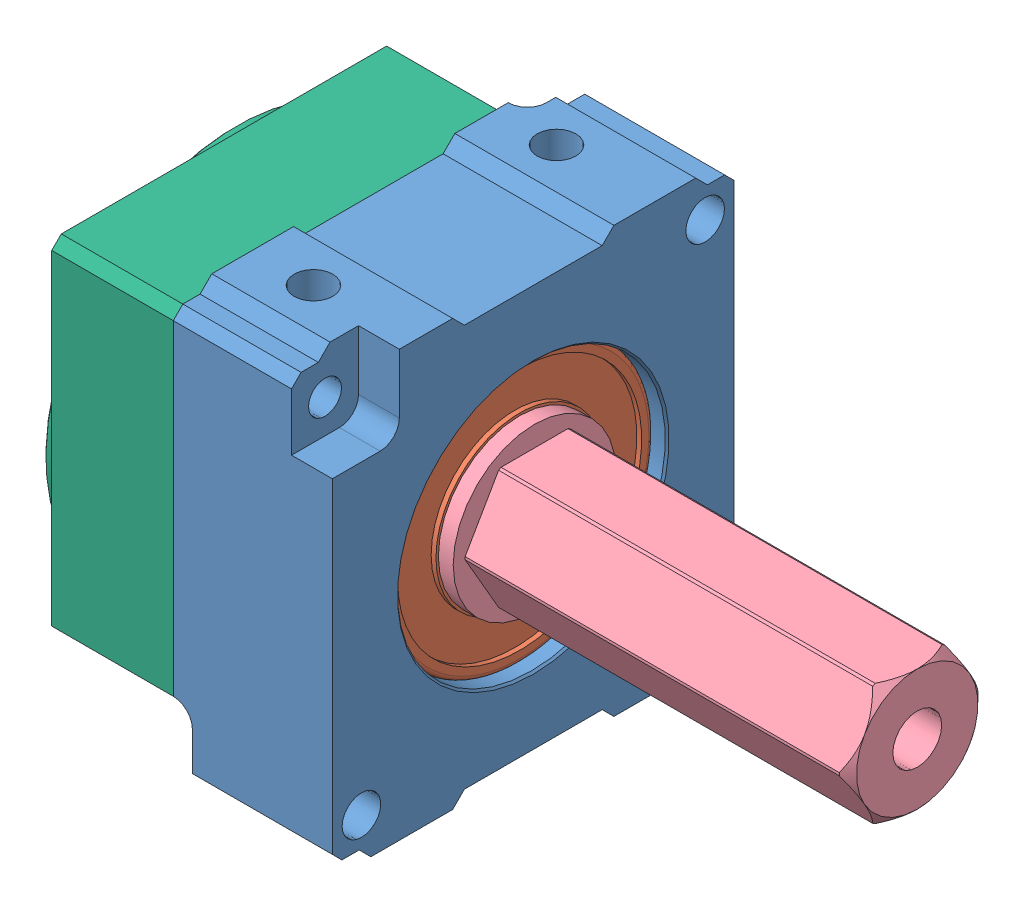
SolidWorks assembly v2-VersaPlanetary-1stage-with-775pro-20161031, configuration Default. Lengths in mm.
Overall size (71.25 44.45 42).
7 component instances, 6 part files, 13 mates.
Components (placement in the parent):
- 217-2625-026 Rev1-1: 217-2625-026 Rev1 [Default] at (-6.2575 -5.0341 -38.5492) x (0 -1 0) z (-1 0 0) size (44.45 42 18.13)
- 217-2742-001 Rev4-1: 217-2742-001 Rev4 [Default] at (-0.4115 -5.0341 -38.5492) x (1 0 0) z (0 0.976211 0.216822) size (7 28 28)
- 217-2742-001 Rev4-2: 217-2742-001 Rev4 [Default] at (8.4427 -5.0341 -38.5492) size (7 28 28)
- 217-2625-017 Rev1_9714K61-1: 217-2625-017 Rev1_9714K61 [Default] at (8.4427 -5.0341 -38.5492) x (0 0.932853 -0.360257) z (0 0.360257 0.932853) size (28.51 4.98 30.18)
- 217-2625-003 Rev1-1: 217-2625-003 Rev1 [Default] at (7.2409 -5.0341 -38.5492) x (0 -1 0) z (1 0 0) size (17 17 64.12)
- 217-2625-018 Rev1_98541A410-1: 217-2625-018 Rev1_98541A410 [Default] at (-0.9115 -4.635 -38.5422) x (1 0 0) z (0 -0.017452 0.999848) size (1 19.6 17.4)
- 217-2816-001 Rev1-1: 217-2816-001 Rev1 [Default] at (-6.1075 -5.0341 -38.5492) x (0 -1 0) z (1 0 0) size (42 42 14.5)
Mates (geometry in assembly coordinates):
- Concentric1: concentric aligned: cylinder of 217-2742-001 Rev4-1 through (-0.4115 -5.0341 -38.5492) axis (-1 0 0) radius 14; cylinder of 217-2742-001 Rev4-2 through (8.4427 -5.0341 -38.5492) axis (-1 0 0) radius 14
- Concentric2: concentric aligned: cylinder of 217-2742-001 Rev4-2 through (8.4427 -5.0341 -38.5492) axis (-1 0 0) radius 14; line of 217-2625-017 Rev1_9714K61-1 through (8.4427 -5.0341 -38.5492) axis (-1 0 0)
- Tangent3: tangent: plane of 217-2742-001 Rev4-2 through (8.4427 3.7159 -38.5492) normal (-1 0 0); face of 217-2625-017 Rev1_9714K61-1
- Tangent4: tangent: plane of 217-2742-001 Rev4-1 through (6.5885 -3.408 -45.8708) normal (1 0 0); face of 217-2625-017 Rev1_9714K61-1
- Concentric3: concentric aligned: cylinder of 217-2625-003 Rev1-1 through (16.9933 -5.0341 -38.5492) axis (-1 0 0) radius 7.4955; cylinder of 217-2625-018 Rev1_98541A410-1 through (-0.4115 -5.0341 -38.5492) axis (-1 0 0) radius 8.7008
- Coincident1: coincident anti-aligned: plane of 217-2625-003 Rev1-1 through (-1.4115 -5.0341 -46.0447) normal (1 0 0); plane of 217-2625-018 Rev1_98541A410-1 through (-1.4115 -4.635 -38.5422) normal (-1 0 0)
- Concentric4: concentric aligned: cylinder of 217-2625-003 Rev1-1 through (16.9933 -5.0341 -38.5492) axis (-1 0 0) radius 7.4955; cylinder of 217-2816-001 Rev1-1 through (0.2435 -5.0341 -38.5492) axis (-1 0 0) radius 19
- Concentric5: concentric aligned: cylinder of 217-2742-001 Rev4-1 through (-0.4115 -5.0341 -38.5492) axis (-1 0 0) radius 14; cylinder of 217-2816-001 Rev1-1 through (0.2435 -5.0341 -38.5492) axis (-1 0 0) radius 19
- Coincident2: coincident anti-aligned: plane of 217-2742-001 Rev4-1 through (-0.4115 -3.1369 -47.0911) normal (-1 0 0); plane of 217-2625-018 Rev1_98541A410-1 through (-0.4115 -4.635 -38.5422) normal (1 0 0)
- Concentric6: concentric anti-aligned: cylinder of 217-2625-026 Rev1-1 through (16.8675 -5.0341 -38.5492) axis (-1 0 0) radius 13.995; cylinder of 217-2625-003 Rev1-1 through (14.9933 -5.0341 -38.5492) axis (1 0 0) radius 8.5
- Coincident3: coincident anti-aligned: plane of 217-2625-026 Rev1-1 through (8.4427 -5.0341 -38.5492) normal (1 0 0); plane of 217-2742-001 Rev4-2 through (8.4427 8.9659 -38.5492) normal (-1 0 0)
- Coincident4: coincident aligned: plane of 217-2625-026 Rev1-1 through (-1.2575 -26.0341 -17.5492) normal (0 0 1); plane of 217-2816-001 Rev1-1 through (0.2425 15.9659 -17.5492) normal (0 0 1)
- Coincident5: coincident anti-aligned: plane of 217-2625-026 Rev1-1 through (0.2425 -5.0341 -38.5492) normal (-1 0 0); plane of 217-2816-001 Rev1-1 through (0.2425 -26.0341 -59.5492) normal (1 0 0)
